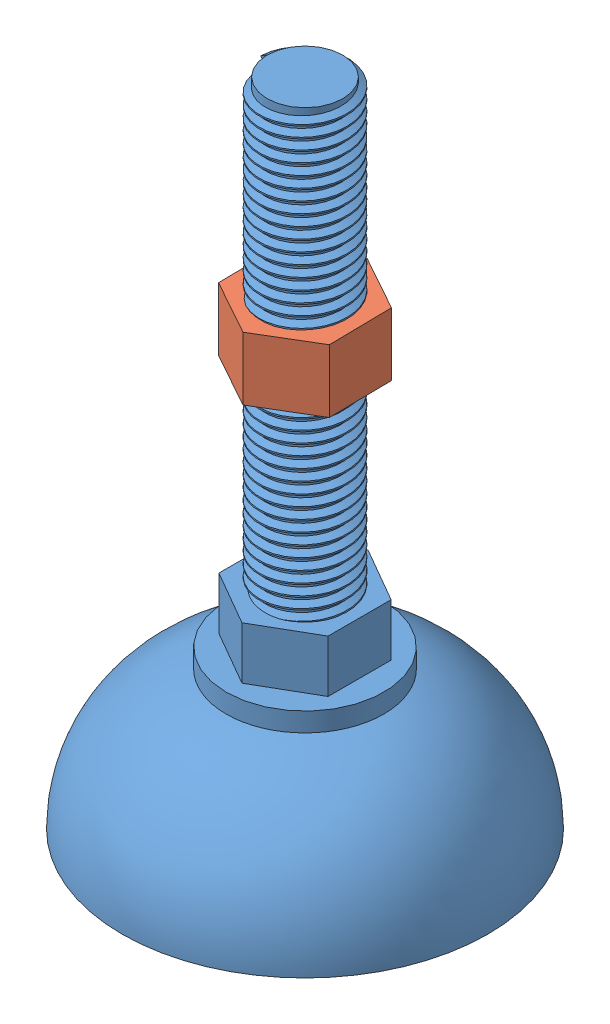
SolidWorks assembly User Library-PIED-M12-57, configuration Défaut. Lengths in mm.
Overall size (58 103.3 58).
2 component instances, 2 part files, 2 mates.
Components (placement in the parent):
- User Library-PIED-M12-57_PIED-M12-57_1-1: User Library-PIED-M12-57_PIED-M12-57_1 [Défaut] at (-5.4111 -51.5788 103.3) size (58 103.3 58)
- User Library-PIED-M12-57_PIED-M12-57_2-1: User Library-PIED-M12-57_PIED-M12-57_2 [Défaut] at (-5.4111 21.7212 103.3) x (-0.015608 0 -0.999878) z (0 -1 0) size (20 17.32 10.61)
Mates (geometry in assembly coordinates):
- Coaxiale1: concentric: circle of PIED-M12-57_1-1; circle of PIED-M12-57_2-1
- Distance1: distance = 30 mm aligned: plane of PIED-M12-57_2-1 through (-5.4111 21.7212 103.3) normal (0 1 0); plane of PIED-M12-57_1-1 through (-5.4111 51.7212 103.3) normal (0 1 0)
